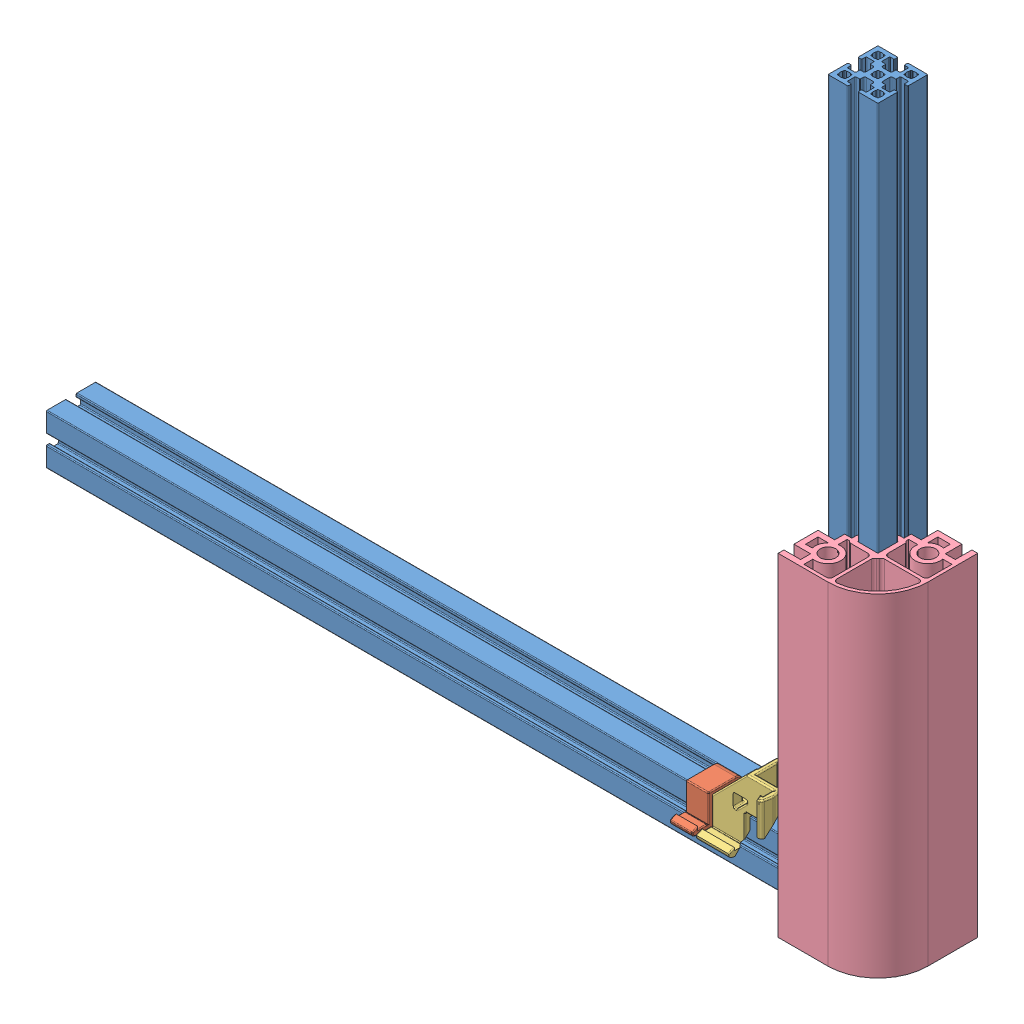
SolidWorks assembly clips, configuration Default. Lengths in mm.
Overall size (265 220 37.4).
12 component instances, 8 part files, 22 mates.
Components (placement in the parent):
- 1515_220mm (4)^clips-1: 1515_220mm (4)^clips [Default] at (37.0172 -218.2801 222.4006) x (0 0 -1) z (1 0 0) size (15 15 220) (virtual)
- deck_clip^clips-1: deck_clip^clips [Default] at origin (suppressed, hidden, virtual)
- v_clip^clips-1: v_clip^clips [Default] at origin size (7 10.35 16.85) (hidden, virtual)
- binding clip^clips-1: binding clip^clips [Default] at (10.1814 0 0) x (1 0 0) z (0 0 1) size (20 10.35 21.7) (hidden, virtual)
- panel_clip^clips-2: panel_clip^clips [Default] at (30.579 0 0) x (1 0 0) z (0 0 1) size (7.02 10.35 15.19) (virtual)
- corner panel_clip^clips-1: corner panel_clip^clips [Default] at (48.539 0 0) x (1 0 0) z (0 0 1) size (20.88 21.83 28.78) (virtual)
- 1515_220mm (4)^clips-2: 1515_220mm (4)^clips [Default] at (-172.9828 31.7199 222.4006) x (0 0 -1) z (0 -1 0) size (15 15 220) (hidden, virtual)
- 1515_220mm (4)^clips-3: 1515_220mm (4)^clips [Default] at (-172.9828 31.7199 207.4006) x (0 0 -1) z (0 -1 0) size (15 15 220) (hidden, virtual)
- 1515_220mm (4)^clips-4: 1515_220mm (4)^clips [Default] at (-157.9828 31.7199 207.4006) x (0 0 -1) z (0 -1 0) size (15 15 220) (hidden, virtual)
- 1515_220mm (4)^clips-5: 1515_220mm (4)^clips [Default] at (-157.9828 31.7199 222.4006) x (0 0 -1) z (0 -1 0) size (15 15 220) (virtual)
- fake_3030_l_shape_with_radius^clips-1: fake_3030_l_shape_with_radius^clips [direct_panels.] at (18.3543 14.5796 -9.6089) size (30 100 30)
- external_panel_mount^clips-1: external_panel_mount^clips [nogap] at (18.3543 126.2291 -9.6089) size (13.65 7 15.65)
Mates (geometry in assembly coordinates):
- Coincident1: coincident anti-aligned: plane of Copy of 1515_220mm (4)^deck_clip-1 through (37.0172 26.7199 22.1506) normal (0 1 0); plane of binding clip^deck_clip-1 through (31.8185 26.7199 0) normal (0 -1 0)
- Coincident6: coincident: plane of Copy of 1515_220mm (4)^deck_clip-1 through (37.0172 20.9699 22.4006) normal (0 0 1); line of binding clip^deck_clip-1 through (17.1814 20.6199 22.4006) axis (-1 0 0)
- Coincident7: coincident anti-aligned: plane of Copy of 1515_220mm (4)^deck_clip-1 through (37.0172 26.7199 22.1506) normal (0 1 0); plane of v_clip^deck_clip-3 through (52.2161 26.7199 25.4506) normal (0 -1 0)
- Coincident9: coincident: plane of Copy of 1515_220mm (4)^deck_clip-1 through (37.0172 20.9699 22.4006) normal (0 0 1); line of v_clip^deck_clip-3 through (37.279 20.6199 22.4006) axis (-1 0 0)
- Coincident10: coincident anti-aligned: plane of Copy of 1515_220mm (4)^deck_clip-1 through (37.0172 26.7199 22.1506) normal (0 1 0); plane of corner panel_clip^deck_clip-1 through (23.9019 26.7199 25.4506) normal (0 -1 0)
- Coincident11: coincident: plane of Copy of 1515_220mm (4)^deck_clip-1 through (37.0172 20.9699 22.4006) normal (0 0 1); line of corner panel_clip^deck_clip-1 through (46.2157 20.6199 22.4006) axis (-1 0 0)
- Coincident12: coincident anti-aligned: plane of Copy of 1515_220mm (4)^deck_clip-1 through (57.0172 19.2199 14.9006) normal (1 0 0); plane of Copy of 1515_220mm (4)^deck_clip-2 through (57.0172 31.7199 16.6506) normal (-1 0 0)
- Coincident13: coincident aligned: plane of Copy of 1515_220mm (4)^deck_clip-1 through (37.0172 11.9699 22.4006) normal (0 0 1); plane of Copy of 1515_220mm (4)^deck_clip-2 through (57.2672 31.7199 22.4006) normal (0 0 1)
- Coincident14: coincident aligned: plane of Copy of 1515_220mm (4)^deck_clip-1 through (37.0172 11.7199 16.6506) normal (0 -1 0); plane of Copy of 1515_220mm (4)^deck_clip-2 through (64.5172 11.7199 14.9006) normal (0 -1 0)
- Coincident15: coincident anti-aligned: plane of 1515_220mm (4)^clips-2 through (72.0172 31.7199 22.1506) normal (1 0 0); plane of 1515_220mm (4)^clips-5 through (72.0172 31.7199 16.6506) normal (-1 0 0)
- Coincident16: coincident aligned: plane of 1515_220mm (4)^clips-2 through (66.2672 31.7199 22.4006) normal (0 0 1); plane of 1515_220mm (4)^clips-5 through (72.2672 31.7199 22.4006) normal (0 0 1)
- Coincident17: coincident aligned: plane of 1515_220mm (4)^clips-2 through (57.0172 31.7199 7.6506) normal (-1 0 0); plane of 1515_220mm (4)^clips-3 through (57.0172 31.7199 1.6506) normal (-1 0 0)
- Coincident18: coincident aligned: plane of 1515_220mm (4)^clips-2 through (64.5172 231.7199 14.9006) normal (0 1 0); plane of 1515_220mm (4)^clips-3 through (64.5172 231.7199 -0.0994) normal (0 1 0)
- Coincident19: coincident aligned: plane of 1515_220mm (4)^clips-2 through (64.5172 231.7199 14.9006) normal (0 1 0); plane of 1515_220mm (4)^clips-5 through (79.5172 231.7199 14.9006) normal (0 1 0)
- Coincident20: coincident anti-aligned: plane of 1515_220mm (4)^clips-2 through (62.7672 31.7199 7.4006) normal (0 0 -1); plane of 1515_220mm (4)^clips-3 through (57.2672 31.7199 7.4006) normal (0 0 1)
- Coincident21: coincident anti-aligned: plane of 1515_220mm (4)^clips-3 through (72.0172 31.7199 -1.8494) normal (1 0 0); plane of 1515_220mm (4)^clips-4 through (72.0172 31.7199 -7.3494) normal (-1 0 0)
- Coincident22: coincident anti-aligned: plane of 1515_220mm (4)^clips-4 through (72.2672 31.7199 7.4006) normal (0 0 1); plane of 1515_220mm (4)^clips-5 through (77.7672 31.7199 7.4006) normal (0 0 -1)
- Coincident23: coincident aligned: plane of 1515_220mm (4)^clips-3 through (64.5172 231.7199 -0.0994) normal (0 1 0); plane of 1515_220mm (4)^clips-4 through (79.5172 231.7199 -0.0994) normal (0 1 0)
- Coincident24: coincident anti-aligned: plane of 1515_220mm (4)^clips-5 through (81.2672 31.7199 22.4006) normal (0 0 1); plane of fake_3030_l_shape_with_radius^clips-1 through (87.0172 64.5796 22.4006) normal (0 0 -1)
- Coincident25: coincident anti-aligned: plane of 1515_220mm (4)^clips-5 through (87.0172 31.7199 22.1506) normal (1 0 0); plane of fake_3030_l_shape_with_radius^clips-1 through (87.0172 64.5796 22.4006) normal (-1 0 0)
- Coincident26: coincident anti-aligned: plane of 1515_220mm (4)^clips-5 through (87.0172 31.7199 22.1506) normal (1 0 0); plane of external_panel_mount^clips-1 through (87.0172 129.7291 22.4006) normal (-1 0 0)
- Coincident27: coincident anti-aligned: plane of 1515_220mm (4)^clips-5 through (72.2672 31.7199 22.4006) normal (0 0 1); plane of external_panel_mount^clips-1 through (87.0172 129.7291 22.4006) normal (0 0 -1)
